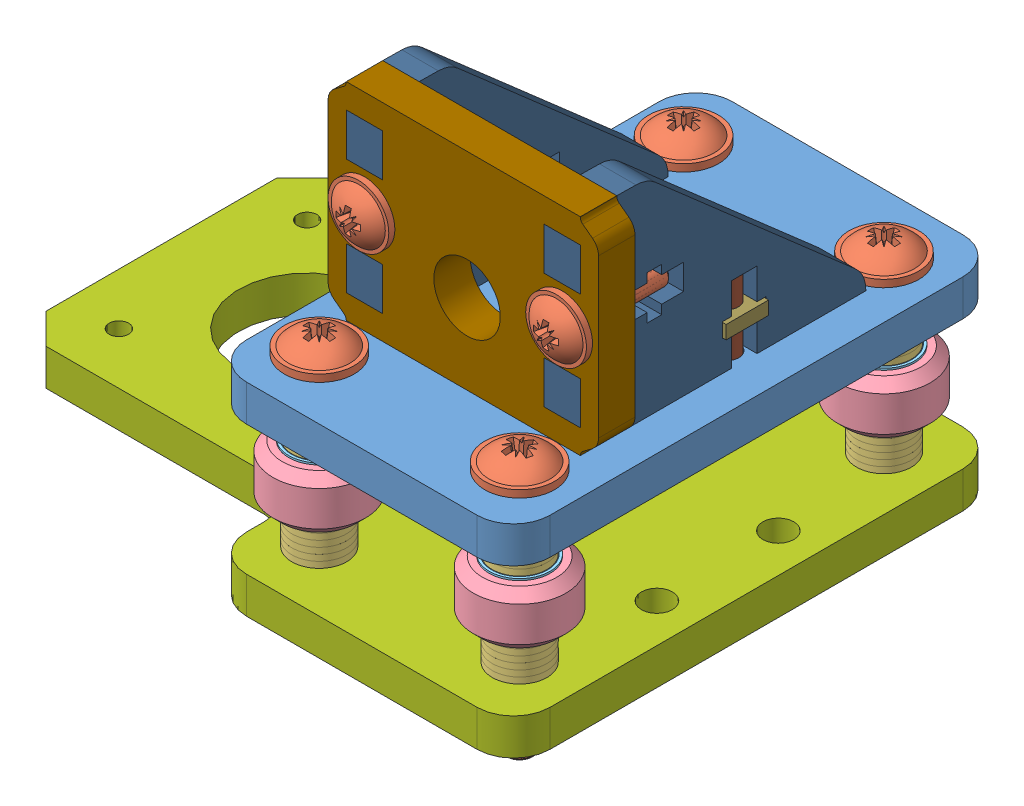
SolidWorks assembly carriage_y_l, configuration По умолчанию. Lengths in mm.
Overall size (131.86 74.07 98.19).
87 component instances, 12 part files, 142 mates.
Components (placement in the parent):
- top_y_l-4: top_y_l [По умолчанию] at origin size (50 6 80)
- DIN967-1: DIN967 [М5х40] at (-17 9.55 -30) x (0 -1 0) z (0 0 1) size (43.47 34 34.42)
- DIN967-2: DIN967 [М5х40] at (-17 9.55 30) x (0 -1 0) z (0 0 1) size (43.47 34 34.42)
- DIN967-3: DIN967 [М5х40] at (16 9.55 -30) x (0 -1 0) z (0 0 1) size (43.47 34 34.42)
- DIN967-4: DIN967 [М5х40] at (16 9.55 30) x (0 -1 0) z (0.973575 0 0.228367) size (43.47 34 34.42)
- din433_m5-1: din433_m5 [По умолчанию] at (16 0 30) x (1 0 0) z (0 -1 0) size (9 9 1)
- din433_m5-2: din433_m5 [По умолчанию] at (16 -2 30) x (-0.882011 0 -0.471229) z (0 1 0) size (9 9 1)
- din433_m5-3: din433_m5 [По умолчанию] at (16 -3 30) x (-0.882011 0 -0.471229) z (0 1 0) size (9 9 1)
- din433_m5-4: din433_m5 [По умолчанию] at (16 -4 30) x (-0.882011 0 -0.471229) z (0 1 0) size (9 9 1)
- din433_m5-5: din433_m5 [По умолчанию] at (16 -5 30) x (-0.986157 0 -0.165812) z (0 1 0) size (9 9 1)
- din433_m5-6: din433_m5 [По умолчанию] at (16 -3 -30) x (-0.882011 0 -0.471229) z (0 1 0) size (9 9 1)
- din433_m5-7: din433_m5 [По умолчанию] at (16 -2 -30) x (-0.882011 0 -0.471229) z (0 1 0) size (9 9 1)
- din433_m5-8: din433_m5 [По умолчанию] at (16 -1 -30) x (-0.706556 0 -0.707657) z (0 1 0) size (9 9 1)
- din433_m5-9: din433_m5 [По умолчанию] at (16 -4 -30) x (-0.882011 0 -0.471229) z (0 1 0) size (9 9 1)
- din433_m5-10: din433_m5 [По умолчанию] at (16 -5 -30) x (0.996128 0 0.087912) z (0 -1 0) size (9 9 1)
- din433_m5-11: din433_m5 [По умолчанию] at (16 -5 -30) x (-0.882011 0 -0.471229) z (0 1 0) size (9 9 1)
- din433_m5-12: din433_m5 [По умолчанию] at (-17 -3 30) x (-0.955012 0 -0.296566) z (0 1 0) size (9 9 1)
- din433_m5-13: din433_m5 [По умолчанию] at (-17 -4 30) x (-0.955012 0 -0.296566) z (0 1 0) size (9 9 1)
- din433_m5-14: din433_m5 [По умолчанию] at (-17 -5 30) x (-0.827257 0 -0.561823) z (0 1 0) size (9 9 1)
- din433_m5-15: din433_m5 [По умолчанию] at (-17 -2 30) x (-0.955012 0 -0.296566) z (0 1 0) size (9 9 1)
- din433_m5-16: din433_m5 [По умолчанию] at (-17 0 30) x (0.982082 0 -0.188455) z (0 -1 0) size (9 9 1)
- din433_m5-17: din433_m5 [По умолчанию] at (-17 -2 -30) x (-0.996489 0 -0.083718) z (0 1 0) size (9 9 1)
- din433_m5-18: din433_m5 [По умолчанию] at (-17 -3 -30) x (-0.996489 0 -0.083718) z (0 1 0) size (9 9 1)
- din433_m5-19: din433_m5 [По умолчанию] at (-17 -4 -30) x (-0.928921 0 -0.370279) z (0 1 0) size (9 9 1)
- din433_m5-20: din433_m5 [По умолчанию] at (-17 -1 -30) x (-0.996489 0 -0.083718) z (0 1 0) size (9 9 1)
- din433_m5-28: din433_m5 [По умолчанию] at (-17 -5 -30) x (0.980186 0 0.198081) z (0 -1 0) size (9 9 1)
- din433_m5-29: din433_m5 [По умолчанию] at (-17 -4 -30) x (0.980186 0 0.198081) z (0 -1 0) size (9 9 1)
- din433_m5-27: din433_m5 [По умолчанию] at (16 -5 30) x (0.91627 0 0.40056) z (0 -1 0) size (9 9 1)
- din433_m5-21: din433_m5 [По умолчанию] at (-17 -6 30) x (-0.552382 0 -0.833591) z (0 1 0) size (9 9 1)
- Delrin Mini V Wheel Kit-1: Delrin Mini V Wheel Kit [По умолчанию] at (-17 -10.7 30) x (0 1 0) z (0 0 1) size (9.4 15.23 15.23)
  - Delrin Mini V Wheel-1: Delrin Mini V Wheel [Default] at origin size (8.8 15.23 15.23)
  - Mini Ball Bearing 105zz 5x10x4-1: Mini Ball Bearing 105zz 5x10x4 [Default] at (2.6 0 0) size (4.2 10 10)
  - Mini Ball Bearing 105zz 5x10x4-2: Mini Ball Bearing 105zz 5x10x4 [Default] at (-2.6 0 0) size (4.2 10 10)
  - Mini V Wheel Precision Shim-2: Mini V Wheel Precision Shim [По умолчанию] at (-0.5 0 0) size (1 8 8)
- din433_m5-30: din433_m5 [По умолчанию] at (-17 -19.4 30) x (0.999952 0 0.009811) z (0 -1 0) size (9 9 1)
- din433_m5-31: din433_m5 [По умолчанию] at (-17 -20.4 30) x (0.999952 0 0.009811) z (0 -1 0) size (9 9 1)
- din433_m5-32: din433_m5 [По умолчанию] at (-17 -16.4 30) x (-0.994411 0 0.105575) z (0 1 0) size (9 9 1)
- din433_m5-33: din433_m5 [По умолчанию] at (-17 -19.4 30) x (-0.982057 0 -0.188585) z (0 1 0) size (9 9 1)
- din433_m5-34: din433_m5 [По умолчанию] at (-17 -18.4 30) x (-0.994411 0 0.105575) z (0 1 0) size (9 9 1)
- din433_m5-35: din433_m5 [По умолчанию] at (-17 -17.4 30) x (-0.994411 0 0.105575) z (0 1 0) size (9 9 1)
- Delrin Mini V Wheel Kit-2: Delrin Mini V Wheel Kit [По умолчанию] at (-17 -10.7 -30) x (0 -1 0) z (0.990454 0 -0.137844) size (9.4 15.23 15.23)
  - Delrin Mini V Wheel-1: Delrin Mini V Wheel [Default] at origin size (8.8 15.23 15.23)
  - Mini Ball Bearing 105zz 5x10x4-1: Mini Ball Bearing 105zz 5x10x4 [Default] at (2.6 0 0) size (4.2 10 10)
  - Mini Ball Bearing 105zz 5x10x4-2: Mini Ball Bearing 105zz 5x10x4 [Default] at (-2.6 0 0) size (4.2 10 10)
  - Mini V Wheel Precision Shim-2: Mini V Wheel Precision Shim [По умолчанию] at (-0.5 0 0) size (1 8 8)
- din433_m5-42: din433_m5 [По умолчанию] at (-17 -20.4 -30) x (0.983884 0 -0.17881) z (0 -1 0) size (9 9 1)
- din433_m5-43: din433_m5 [По умолчанию] at (-17 -16.4 -30) x (-0.956697 0 0.291085) z (0 1 0) size (9 9 1)
- din433_m5-44: din433_m5 [По умолчанию] at (-17 -19.4 -30) x (-1 0 -0.000132) z (0 1 0) size (9 9 1)
- din433_m5-45: din433_m5 [По умолчанию] at (-17 -18.4 -30) x (-0.956697 0 0.291085) z (0 1 0) size (9 9 1)
- din433_m5-46: din433_m5 [По умолчанию] at (-17 -17.4 -30) x (-0.956697 0 0.291085) z (0 1 0) size (9 9 1)
- din433_m5-47: din433_m5 [По умолчанию] at (-17 -19.4 -30) x (0.983884 0 -0.17881) z (0 -1 0) size (9 9 1)
- Delrin Mini V Wheel Kit-3: Delrin Mini V Wheel Kit [По умолчанию] at (16 -10.7 -30) x (0 1 0) z (0 0 1) size (9.4 15.23 15.23)
  - Delrin Mini V Wheel-1: Delrin Mini V Wheel [Default] at origin size (8.8 15.23 15.23)
  - Mini Ball Bearing 105zz 5x10x4-1: Mini Ball Bearing 105zz 5x10x4 [Default] at (2.6 0 0) size (4.2 10 10)
  - Mini Ball Bearing 105zz 5x10x4-2: Mini Ball Bearing 105zz 5x10x4 [Default] at (-2.6 0 0) size (4.2 10 10)
  - Mini V Wheel Precision Shim-2: Mini V Wheel Precision Shim [По умолчанию] at (-0.5 0 0) size (1 8 8)
- Delrin Mini V Wheel Kit-4: Delrin Mini V Wheel Kit [По умолчанию] at (16 -10.7 30) x (0 -1 0) z (-0.546944 0 0.837169) size (9.4 15.23 15.23)
  - Delrin Mini V Wheel-1: Delrin Mini V Wheel [Default] at origin size (8.8 15.23 15.23)
  - Mini Ball Bearing 105zz 5x10x4-1: Mini Ball Bearing 105zz 5x10x4 [Default] at (2.6 0 0) size (4.2 10 10)
  - Mini Ball Bearing 105zz 5x10x4-2: Mini Ball Bearing 105zz 5x10x4 [Default] at (-2.6 0 0) size (4.2 10 10)
  - Mini V Wheel Precision Shim-2: Mini V Wheel Precision Shim [По умолчанию] at (-0.5 0 0) size (1 8 8)
- din433_m5-54: din433_m5 [По умолчанию] at (16 -16.4 30) x (-0.124351 0 0.992238) z (0 1 0) size (9 9 1)
- din433_m5-55: din433_m5 [По умолчанию] at (16 -19.4 30) x (-0.982107 0 0.188325) z (0 1 0) size (9 9 1)
- din433_m5-56: din433_m5 [По умолчанию] at (16 -18.4 30) x (-0.884699 0 0.466164) z (0 1 0) size (9 9 1)
- din433_m5-57: din433_m5 [По умолчанию] at (16 -17.4 30) x (-0.884699 0 0.466164) z (0 1 0) size (9 9 1)
- din433_m5-58: din433_m5 [По умолчанию] at (16 -19.4 30) x (0.932557 0 -0.361024) z (0 -1 0) size (9 9 1)
- din433_m5-59: din433_m5 [По умолчанию] at (16 -20.4 30) x (0.932557 0 -0.361024) z (0 -1 0) size (9 9 1)
- din433_m5-132: din433_m5 [По умолчанию] at (16 -18.4 -30) x (-0.884699 0 0.466164) z (0 1 0) size (9 9 1)
- din433_m5-133: din433_m5 [По умолчанию] at (16 -20.4 -30) x (0.932557 0 -0.361024) z (0 -1 0) size (9 9 1)
- din433_m5-134: din433_m5 [По умолчанию] at (16 -19.4 -30) x (0.932557 0 -0.361024) z (0 -1 0) size (9 9 1)
- din433_m5-135: din433_m5 [По умолчанию] at (16 -17.4 -30) x (-0.884699 0 0.466164) z (0 1 0) size (9 9 1)
- din433_m5-136: din433_m5 [По умолчанию] at (16 -19.4 -30) x (-0.982107 0 0.188325) z (0 1 0) size (9 9 1)
- din433_m5-137: din433_m5 [По умолчанию] at (16 -16.4 -30) x (0.998156 0 0.060708) z (0 1 0) size (9 9 1)
- bottom_y_l-2: bottom_y_l [По умолчанию] at (0 -27.4 0) size (131.86 6 80)
- DIN 985-1: DIN 985 [Verzle DIN 985 - M5] at (-17 -27.4 -30) x (0 1 0) z (1 0 0) size (5 9.24 8)
- DIN 985-2: DIN 985 [Verzle DIN 985 - M5] at (-17 -27.4 30) x (0 1 0) z (1 0 0) size (5 9.24 8)
- DIN 985-3: DIN 985 [Verzle DIN 985 - M5] at (16 -27.4 -30) x (0 1 0) z (1 0 0) size (5 9.24 8)
- DIN 985-4: DIN 985 [Verzle DIN 985 - M5] at (16 -27.4 30) x (0 1 0) z (1 0 0) size (5 9.24 8)
- carriage_y_console-1: carriage_y_console [По умолчанию] at (3.7454 -0.1715 23) x (-1 0 0) z (0 0 -1) size (44.55 34.07 6)
- carriage_y_console_rectangel-1: carriage_y_console_rectangel [По умолчанию] at (19 -0.0784 23) x (0 0 -1) z (1 0 0) size (47 40.07 6)
- carriage_y_console_rectangel-2: carriage_y_console_rectangel [По умолчанию] at (-13.55 -0.0784 23) x (0 0 -1) z (1 0 0) size (47 40.07 6)
- DIN 7991-1: DIN 7991 [ISO 7991 M04 x  16] at (-16.55 0 -4) x (0 1 0) z (-1 0 0) size (18.3 40 22.08)
- din 562 m4din-1: din 562 m4din [По умолчанию] at (-16.55 11 -4) x (0 0 -1) z (0 1 0) size (7 7 2.2)
- DIN 7991-2: DIN 7991 [ISO 7991 M04 x  16] at (16 0 -4) x (0 1 0) z (1 0 0) size (18.3 40 22.08)
- din 562 m4din-2: din 562 m4din [По умолчанию] at (16 11 -4) x (0 0 1) z (0 1 0) size (7 7 2.2)
- DIN967-5: DIN967 [M4х16] at (-16.55 23 26.05) x (0 0 -1) z (1 0 0) size (18.96 34 34.42)
- DIN967-6: DIN967 [M4х16] at (16 23 26.05) x (0 0 -1) z (1 0 0) size (18.96 34 34.42)
Mates (geometry in assembly coordinates):
- Концентричный11: concentric anti-aligned: cylinder of top-4 through (-17 6 -30) axis (0 -1 0) radius 2.55; cylinder of DIN967-1 through (-17 15.9 -30) axis (0 1 0) radius 5.75
- Совпадение11: coincident anti-aligned: plane of top-4 through (19 6 -34) normal (0 1 0); plane of DIN967-1 through (-14.5 6 -30) normal (0 -1 0)
- Концентричный21: concentric anti-aligned: cylinder of top-4 through (-17 6 30) axis (0 -1 0) radius 2.55; cylinder of DIN967-2 through (-17 15.9 30) axis (0 1 0) radius 5.75
- Совпадение21: coincident anti-aligned: plane of top-4 through (19 6 -34) normal (0 1 0); plane of DIN967-2 through (-14.5 6 30) normal (0 -1 0)
- Концентричный31: concentric anti-aligned: cylinder of DIN967-3 through (16 15.9 -30) axis (0 1 0) radius 5.75; circle of carriage_axis_y_plywood_left-1
- Совпадение31: coincident anti-aligned: plane of top-4 through (19 6 -34) normal (0 1 0); plane of DIN967-3 through (18.5 6 -30) normal (0 -1 0)
- Совпадение41: coincident anti-aligned: plane of top-4 through (19 6 -34) normal (0 1 0); plane of DIN967-4 through (16.5709 6 27.5661) normal (0 -1 0)
- Концентричный5: concentric anti-aligned: cylinder of top-4 through (16 6 30) axis (0 -1 0) radius 2.55; cylinder of DIN967-4 through (16 15.9 30) axis (0 1 0) radius 2.5
- Совпадение5: coincident anti-aligned: plane of top-4 through (19 0 -34) normal (0 -1 0); plane of din433_m5-1 through (16 0 30) normal (0 1 0)
- Концентричный6: concentric anti-aligned: cylinder of DIN967-4 through (16 15.9 30) axis (0 1 0) radius 2.5; circle of din433_m5-1
- Концентричный7: concentric aligned: cylinder of DIN967-4 through (16 15.9 30) axis (0 1 0) radius 2.5; circle of din433_m5-2
- Совпадение7: coincident anti-aligned: plane of din433_m5-1 through (16 -1 30) normal (0 -1 0); plane of din433_m5-2 through (16 -1 30) normal (0 1 0)
- Совпадение10: coincident anti-aligned: plane of din433_m5-3 through (16 -3 30) normal (0 -1 0); plane of din433_m5-4 through (16 -3 30) normal (0 1 0)
- Совпадение11: coincident aligned: circle of din433_m5-3; circle of din433_m5-4
- Совпадение12: coincident anti-aligned: plane of din433_m5-4 through (16 -4 30) normal (0 -1 0); plane of din433_m5-5 through (16 -4 30) normal (0 1 0)
- Совпадение13: coincident aligned: circle of din433_m5-4; circle of din433_m5-5
- Совпадение14: coincident anti-aligned: plane of din433_m5-2 through (16 -2 30) normal (0 -1 0); plane of din433_m5-3 through (16 -2 30) normal (0 1 0)
- Совпадение15: coincident aligned: circle of din433_m5-2; circle of din433_m5-3
- Совпадение16: coincident anti-aligned: plane of top-4 through (19 0 -34) normal (0 -1 0); plane of din433_m5-8 through (16 0 -30) normal (0 1 0)
- Концентричный8: concentric aligned: cylinder of DIN967-3 through (16 15.9 -30) axis (0 1 0) radius 2.5; circle of din433_m5-8
- Совпадение17: coincident anti-aligned: plane of din433_m5-7 through (16 -1 -30) normal (0 1 0); plane of din433_m5-8 through (16 -1 -30) normal (0 -1 0)
- Совпадение18: coincident aligned: circle of din433_m5-7; circle of din433_m5-8
- Совпадение19: coincident anti-aligned: plane of din433_m5-6 through (16 -2 -30) normal (0 1 0); plane of din433_m5-7 through (16 -2 -30) normal (0 -1 0)
- Концентричный9: concentric aligned: cylinder of DIN967-3 through (16 15.9 -30) axis (0 1 0) radius 2.5; circle of din433_m5-6
- Совпадение20: coincident anti-aligned: plane of din433_m5-6 through (16 -3 -30) normal (0 -1 0); plane of din433_m5-9 through (16 -3 -30) normal (0 1 0)
- Концентричный10: concentric aligned: cylinder of DIN967-3 through (16 15.9 -30) axis (0 1 0) radius 2.5; circle of din433_m5-9
- Совпадение22: coincident anti-aligned: plane of din433_m5-9 through (16 -4 -30) normal (0 -1 0); plane of din433_m5-11 through (16 -4 -30) normal (0 1 0)
- Концентричный11: concentric aligned: cylinder of DIN967-3 through (16 15.9 -30) axis (0 1 0) radius 2.5; circle of din433_m5-11
- Совпадение23: coincident anti-aligned: plane of din433_m5-10 through (16 -5 -30) normal (0 1 0); plane of din433_m5-11 through (16 -5 -30) normal (0 -1 0)
- Концентричный13: concentric anti-aligned: cylinder of DIN967-3 through (16 15.9 -30) axis (0 1 0) radius 2.5; circle of din433_m5-10
- Совпадение24: coincident anti-aligned: plane of din433_m5-15 through (-17 -1 30) normal (0 1 0); plane of din433_m5-16 through (-17 -1 30) normal (0 -1 0)
- Совпадение25: coincident anti-aligned: plane of din433_m5-12 through (-17 -3 30) normal (0 -1 0); plane of din433_m5-13 through (-17 -3 30) normal (0 1 0)
- Совпадение26: coincident aligned: circle of din433_m5-12; circle of din433_m5-13
- Совпадение27: coincident anti-aligned: plane of din433_m5-13 through (-17 -4 30) normal (0 -1 0); plane of din433_m5-14 through (-17 -4 30) normal (0 1 0)
- Совпадение28: coincident aligned: circle of din433_m5-13; circle of din433_m5-14
- Совпадение29: coincident anti-aligned: plane of din433_m5-12 through (-17 -2 30) normal (0 1 0); plane of din433_m5-15 through (-17 -2 30) normal (0 -1 0)
- Совпадение30: coincident aligned: circle of din433_m5-12; circle of din433_m5-15
- Совпадение33: coincident anti-aligned: plane of din433_m5-17 through (-17 -2 -30) normal (0 -1 0); plane of din433_m5-18 through (-17 -2 -30) normal (0 1 0)
- Совпадение34: coincident aligned: circle of din433_m5-17; circle of din433_m5-18
- Совпадение35: coincident anti-aligned: plane of din433_m5-18 through (-17 -3 -30) normal (0 -1 0); plane of din433_m5-19 through (-17 -3 -30) normal (0 1 0)
- Совпадение36: coincident aligned: circle of din433_m5-18; circle of din433_m5-19
- Совпадение37: coincident anti-aligned: plane of din433_m5-17 through (-17 -1 -30) normal (0 1 0); plane of din433_m5-20 through (-17 -1 -30) normal (0 -1 0)
- Совпадение38: coincident aligned: circle of din433_m5-17; circle of din433_m5-20
- Концентричный15: concentric aligned: cylinder of DIN967-2 through (-17 15.9 30) axis (0 1 0) radius 2.5; circle of din433_m5-14
- Концентричный16: concentric anti-aligned: cylinder of DIN967-2 through (-17 15.9 30) axis (0 1 0) radius 2.5; circle of din433_m5-16
- Совпадение54: coincident anti-aligned: plane of din433_m5-14 through (-17 -5 30) normal (0 -1 0); plane of din433_m5-21 through (-17 -5 30) normal (0 1 0)
- Концентричный17: concentric aligned: cylinder of DIN967-2 through (-17 15.9 30) axis (0 1 0) radius 2.5; circle of din433_m5-21
- Совпадение55: coincident anti-aligned: plane of din433_m5-5 through (16 -5 30) normal (0 -1 0); plane of din433_m5-27 through (16 -5 30) normal (0 1 0)
- Концентричный18: concentric anti-aligned: cylinder of DIN967-4 through (16 15.9 30) axis (0 1 0) radius 2.5; circle of din433_m5-27
- Концентричный19: concentric aligned: cylinder of DIN967-1 through (-17 15.9 -30) axis (0 1 0) radius 2.5; circle of din433_m5-20
- Совпадение56: coincident anti-aligned: plane of din433_m5-19 through (-17 -4 -30) normal (0 -1 0); plane of din433_m5-29 through (-17 -4 -30) normal (0 1 0)
- Концентричный20: concentric anti-aligned: cylinder of DIN967-1 through (-17 15.9 -30) axis (0 1 0) radius 2.5; circle of din433_m5-29
- Совпадение57: coincident anti-aligned: plane of din433_m5-28 through (-17 -5 -30) normal (0 1 0); plane of din433_m5-29 through (-17 -5 -30) normal (0 -1 0)
- Концентричный21: concentric anti-aligned: cylinder of DIN967-1 through (-17 15.9 -30) axis (0 1 0) radius 2.5; circle of din433_m5-28
- Совпадение58: coincident anti-aligned: plane of top-4 through (19 0 -34) normal (0 -1 0); plane of din433_m5-20 through (-17 0 -30) normal (0 1 0)
- Совпадение59: coincident anti-aligned: plane of din433_m5-21 through (-17 -6 30) normal (0 -1 0); plane of Delrin Mini V Wheel Kit-1/Mini Ball Bearing 105zz 5x10x4-1 through (-19.5 -6 30) normal (0 1 0)
- Совпадение60: coincident aligned: cylinder of DIN967-2 through (-17 15.9 30) axis (0 1 0) radius 2.5; circle of Delrin Mini V Wheel Kit-1/Mini Ball Bearing 105zz 5x10x4-2
- Совпадение61: coincident anti-aligned: plane of din433_m5-34 through (-17 -17.4 30) normal (0 1 0); plane of din433_m5-35 through (-17 -17.4 30) normal (0 -1 0)
- Совпадение62: coincident aligned: circle of din433_m5-34; circle of din433_m5-35
- Совпадение63: coincident anti-aligned: plane of din433_m5-33 through (-17 -18.4 30) normal (0 1 0); plane of din433_m5-34 through (-17 -18.4 30) normal (0 -1 0)
- Совпадение64: coincident aligned: circle of din433_m5-33; circle of din433_m5-34
- Совпадение65: coincident anti-aligned: plane of din433_m5-32 through (-17 -16.4 30) normal (0 -1 0); plane of din433_m5-35 through (-17 -16.4 30) normal (0 1 0)
- Совпадение67: coincident anti-aligned: plane of din433_m5-30 through (-17 -19.4 30) normal (0 1 0); plane of din433_m5-33 through (-17 -19.4 30) normal (0 -1 0)
- Совпадение68: coincident anti-aligned: plane of din433_m5-30 through (-17 -20.4 30) normal (0 -1 0); plane of din433_m5-31 through (-17 -20.4 30) normal (0 1 0)
- Совпадение80: coincident anti-aligned: plane of Delrin Mini V Wheel Kit-1/Mini Ball Bearing 105zz 5x10x4-2 through (-19.5 -15.4 30) normal (0 -1 0); plane of din433_m5-32 through (-17 -15.4 30) normal (0 1 0)
- Концентричный22: concentric aligned: cylinder of DIN967-2 through (-17 15.9 30) axis (0 1 0) radius 2.5; circle of din433_m5-32
- Концентричный23: concentric aligned: cylinder of DIN967-2 through (-17 15.9 30) axis (0 1 0) radius 2.5; circle of din433_m5-35
- Концентричный24: concentric anti-aligned: cylinder of DIN967-2 through (-17 15.9 30) axis (0 1 0) radius 2.5; circle of din433_m5-30
- Концентричный25: concentric aligned: cylinder of DIN967-2 through (-17 15.9 30) axis (0 1 0) radius 2.5; cylinder of din433_m5-31 through (-17 -21.4 30) axis (0 1 0) radius 4.5
- Совпадение81: coincident anti-aligned: plane of din433_m5-28 through (-17 -6 -30) normal (0 -1 0); plane of Delrin Mini V Wheel Kit-2/Mini Ball Bearing 105zz 5x10x4-2 through (-17.3446 -6 -32.4761) normal (0 1 0)
- Совпадение82: coincident anti-aligned: cylinder of DIN967-1 through (-17 15.9 -30) axis (0 1 0) radius 2.5; circle of Delrin Mini V Wheel Kit-2/Mini Ball Bearing 105zz 5x10x4-1
- Совпадение83: coincident anti-aligned: plane of din433_m5-45 through (-17 -17.4 -30) normal (0 1 0); plane of din433_m5-46 through (-17 -17.4 -30) normal (0 -1 0)
- Совпадение84: coincident aligned: circle of din433_m5-45; circle of din433_m5-46
- Совпадение85: coincident anti-aligned: plane of din433_m5-44 through (-17 -18.4 -30) normal (0 1 0); plane of din433_m5-45 through (-17 -18.4 -30) normal (0 -1 0)
- Совпадение86: coincident aligned: circle of din433_m5-44; circle of din433_m5-45
- Совпадение87: coincident anti-aligned: plane of din433_m5-43 through (-17 -16.4 -30) normal (0 -1 0); plane of din433_m5-46 through (-17 -16.4 -30) normal (0 1 0)
- Совпадение88: coincident anti-aligned: plane of din433_m5-44 through (-17 -19.4 -30) normal (0 -1 0); plane of din433_m5-47 through (-17 -19.4 -30) normal (0 1 0)
- Совпадение89: coincident anti-aligned: plane of din433_m5-42 through (-17 -20.4 -30) normal (0 1 0); plane of din433_m5-47 through (-17 -20.4 -30) normal (0 -1 0)
- Совпадение99: coincident anti-aligned: plane of top-4 through (19 0 -34) normal (0 -1 0); plane of din433_m5-16 through (-17 0 30) normal (0 1 0)
- Совпадение100: coincident anti-aligned: plane of Delrin Mini V Wheel Kit-2/Mini Ball Bearing 105zz 5x10x4-1 through (-17.3446 -15.4 -32.4761) normal (0 -1 0); plane of din433_m5-43 through (-17 -15.4 -30) normal (0 1 0)
- Концентричный26: concentric anti-aligned: circle of din433_m5-42; circle of din433_m5-43
- Концентричный27: concentric anti-aligned: circle of din433_m5-43; circle of din433_m5-47
- Концентричный28: concentric anti-aligned: circle of din433_m5-42; circle of din433_m5-44
- Концентричный29: concentric aligned: circle of Delrin Mini V Wheel Kit-2/Mini Ball Bearing 105zz 5x10x4-1; cylinder of din433_m5-43 through (-17 -15.4 -30) axis (0 -1 0) radius 4.5
- Совпадение104: coincident anti-aligned: plane of din433_m5-10 through (16 -6 -30) normal (0 -1 0); plane of Delrin Mini V Wheel Kit-3/Mini Ball Bearing 105zz 5x10x4-1 through (13.5 -6 -30) normal (0 1 0)
- Совпадение105: coincident aligned: cylinder of DIN967-3 through (16 15.9 -30) axis (0 1 0) radius 2.5; circle of Delrin Mini V Wheel Kit-3/Mini Ball Bearing 105zz 5x10x4-2
- Совпадение106: coincident anti-aligned: plane of din433_m5-27 through (16 -6 30) normal (0 -1 0); plane of Delrin Mini V Wheel Kit-4/Mini Ball Bearing 105zz 5x10x4-2 through (18.0929 -6 31.3674) normal (0 1 0)
- Концентричный30: concentric anti-aligned: cylinder of DIN967-4 through (16 15.9 30) axis (0 1 0) radius 2.5; cylinder of Delrin Mini V Wheel Kit-4/Mini Ball Bearing 105zz 5x10x4-1 through (16 -13.3 30) axis (0 -1 0) radius 2.5
- Совпадение107: coincident anti-aligned: plane of din433_m5-56 through (16 -17.4 30) normal (0 1 0); plane of din433_m5-57 through (16 -17.4 30) normal (0 -1 0)
- Совпадение108: coincident aligned: circle of din433_m5-56; circle of din433_m5-57
- Совпадение109: coincident anti-aligned: plane of din433_m5-55 through (16 -18.4 30) normal (0 1 0); plane of din433_m5-56 through (16 -18.4 30) normal (0 -1 0)
- Совпадение110: coincident aligned: circle of din433_m5-55; circle of din433_m5-56
- Совпадение111: coincident anti-aligned: plane of din433_m5-54 through (16 -16.4 30) normal (0 -1 0); plane of din433_m5-57 through (16 -16.4 30) normal (0 1 0)
- Совпадение112: coincident anti-aligned: plane of din433_m5-55 through (16 -19.4 30) normal (0 -1 0); plane of din433_m5-58 through (16 -19.4 30) normal (0 1 0)
- Совпадение113: coincident anti-aligned: plane of din433_m5-58 through (16 -20.4 30) normal (0 -1 0); plane of din433_m5-59 through (16 -20.4 30) normal (0 1 0)
- Концентричный31: concentric anti-aligned: circle of din433_m5-54; circle of din433_m5-59
- Концентричный32: concentric anti-aligned: circle of din433_m5-54; circle of din433_m5-58
- Концентричный33: concentric anti-aligned: circle of din433_m5-55; circle of din433_m5-59
- Концентричный83: concentric anti-aligned: circle of din433_m5-133; circle of din433_m5-136
- Совпадение200: coincident anti-aligned: plane of din433_m5-132 through (16 -18.4 -30) normal (0 -1 0); plane of din433_m5-136 through (16 -18.4 -30) normal (0 1 0)
- Совпадение201: coincident aligned: circle of din433_m5-132; circle of din433_m5-135
- Совпадение202: coincident anti-aligned: plane of din433_m5-132 through (16 -17.4 -30) normal (0 1 0); plane of din433_m5-135 through (16 -17.4 -30) normal (0 -1 0)
- Концентричный84: concentric anti-aligned: circle of din433_m5-134; circle of din433_m5-137
- Совпадение203: coincident anti-aligned: plane of din433_m5-135 through (16 -16.4 -30) normal (0 1 0); plane of din433_m5-137 through (16 -16.4 -30) normal (0 -1 0)
- Концентричный85: concentric anti-aligned: circle of din433_m5-133; circle of din433_m5-137
- Совпадение204: coincident anti-aligned: plane of din433_m5-134 through (16 -19.4 -30) normal (0 1 0); plane of din433_m5-136 through (16 -19.4 -30) normal (0 -1 0)
- Совпадение205: coincident aligned: circle of din433_m5-132; circle of din433_m5-136
- Совпадение206: coincident anti-aligned: plane of din433_m5-133 through (16 -20.4 -30) normal (0 1 0); plane of din433_m5-134 through (16 -20.4 -30) normal (0 -1 0)
- Совпадение207: coincident anti-aligned: plane of Delrin Mini V Wheel Kit-3/Mini Ball Bearing 105zz 5x10x4-2 through (13.5 -15.4 -30) normal (0 -1 0); plane of din433_m5-137 through (16 -15.4 -30) normal (0 1 0)
- Концентричный86: concentric aligned: cylinder of DIN967-3 through (16 15.9 -30) axis (0 1 0) radius 2.5; circle of din433_m5-137
- Совпадение208: coincident anti-aligned: plane of Delrin Mini V Wheel Kit-4/Mini Ball Bearing 105zz 5x10x4-1 through (18.0929 -15.4 31.3674) normal (0 -1 0); plane of din433_m5-54 through (16 -15.4 30) normal (0 1 0)
- Концентричный87: concentric aligned: cylinder of DIN967-4 through (16 15.9 30) axis (0 1 0) radius 2.5; circle of din433_m5-54
- Концентричный88: concentric anti-aligned: cylinder of DIN967-1 through (-17 15.9 -30) axis (0 1 0) radius 2.5; circle of carriage_axis_y_plywood_left-2
- Концентричный89: concentric anti-aligned: cylinder of DIN967-2 through (-17 15.9 30) axis (0 1 0) radius 2.5; circle of carriage_axis_y_plywood_left-2
- Совпадение210: coincident anti-aligned: plane of din433_m5-42 through (-17 -21.4 -30) normal (0 -1 0); plane of bottom_y_l-2 through (19 -21.4 -34) normal (0 1 0)
- Совпадение211: coincident anti-aligned: plane of bottom_y_l-2 through (19 -27.4 -34) normal (0 -1 0); plane of DIN 985-1 through (-17 -27.4 -30) normal (0 1 0)
- Концентричный90: concentric anti-aligned: cylinder of DIN967-1 through (-17 15.9 -30) axis (0 1 0) radius 2.5; cylinder of DIN 985-1 through (-17 -35.522 -30) axis (0 -1 0) radius 2.5
- Совпадение212: coincident anti-aligned: plane of bottom_y_l-2 through (19 -27.4 -34) normal (0 -1 0); plane of DIN 985-2 through (-17 -27.4 30) normal (0 1 0)
- Совпадение213: coincident anti-aligned: plane of bottom_y_l-2 through (19 -27.4 -34) normal (0 -1 0); plane of DIN 985-4 through (16 -27.4 30) normal (0 1 0)
- Совпадение214: coincident anti-aligned: plane of bottom_y_l-2 through (19 -27.4 -34) normal (0 -1 0); plane of DIN 985-3 through (16 -27.4 -30) normal (0 1 0)
- Концентричный91: concentric anti-aligned: cylinder of DIN967-2 through (-17 15.9 30) axis (0 1 0) radius 2.5; cylinder of DIN 985-2 through (-17 -35.522 30) axis (0 -1 0) radius 2.5
- Концентричный92: concentric anti-aligned: cylinder of DIN967-3 through (16 15.9 -30) axis (0 1 0) radius 2.5; cylinder of DIN 985-3 through (16 -35.522 -30) axis (0 -1 0) radius 2.5
- Концентричный93: concentric anti-aligned: cylinder of DIN967-4 through (16 15.9 30) axis (0 1 0) radius 2.5; cylinder of DIN 985-4 through (16 -35.522 30) axis (0 -1 0) radius 2.5
- Расстояние1: distance = 17 mm aligned: plane of carriage_y_console-1 through (3.7454 -0.1715 23) normal (0 0 1); plane of top_y_l-4 through (-19 6 40) normal (0 0 1)
- Совпадение224: coincident anti-aligned: plane of carriage_y_console-1 through (3.7454 -0.1715 17) normal (0 0 -1); plane of carriage_y_console_rectangel-2 through (-19.55 40.0693 17) normal (0 0 1)
- Совпадение225: coincident anti-aligned: plane of top_y_l-4 through (19 6 -34) normal (0 1 0); plane of carriage_y_console_rectangel-2 through (-19.55 6 -24) normal (0 -1 0)
- Совпадение226: coincident aligned: plane of carriage_y_console-1 through (-19.55 6 17) normal (-1 0 0); plane of carriage_y_console_rectangel-2 through (-19.55 6.2312 -19) normal (-1 0 0)
- Совпадение227: coincident anti-aligned: plane of top_y_l-4 through (19 6 -34) normal (0 1 0); plane of carriage_y_console-1 through (19 6 17) normal (0 -1 0)
- Расстояние3: distance = 5.45 mm aligned: plane of top_y_l-4 through (-25 6 34) normal (-1 0 0); plane of carriage_y_console-1 through (-19.55 6 17) normal (-1 0 0)
- Совпадение228: coincident aligned: plane of carriage_y_console-1 through (3.7454 -0.1715 23) normal (0 0 1); plane of carriage_y_console_rectangel-1 through (19 9.9682 23) normal (0 0 1)
- Совпадение233: coincident anti-aligned: plane of carriage_y_console_rectangel-2 through (-19.55 6.2312 -19) normal (-1 0 0); plane of DIN 7991-1 through (-19.55 0 -4) normal (1 0 0)
- Совпадение234: coincident aligned: plane of top_y_l-4 through (19 0 -34) normal (0 -1 0); plane of DIN 7991-1 through (-16.55 0 -4) normal (0 -1 0)
- Совпадение235: coincident aligned: plane of carriage_y_console_rectangel-2 through (-19.55 6 -24) normal (0 0 -1); plane of DIN 7991-1 through (-16.55 0 -24) normal (0 0 -1)
- Совпадение239: coincident: point of din 562 m4din-1; line of DIN 7991-1 through (-16.55 18.3 -4) axis (0 -1 0)
- Совпадение241: coincident anti-aligned: plane of carriage_y_console_rectangel-1 through (19 6.2312 -19) normal (1 0 0); plane of DIN 7991-2 through (19 0 -4) normal (-1 0 0)
- Совпадение242: coincident aligned: plane of top_y_l-4 through (19 0 -34) normal (0 -1 0); plane of DIN 7991-2 through (16 0 -4) normal (0 -1 0)
- Совпадение243: coincident anti-aligned: plane of carriage_y_console_rectangel-1 through (13 6 -24) normal (0 0 -1); plane of DIN 7991-2 through (16 0 -24) normal (0 0 1)
- Совпадение248: coincident: point of din 562 m4din-2; line of DIN 7991-2 through (16 18.3 -4) axis (0 -1 0)
- Концентричный991: concentric aligned: cylinder of carriage_y_console-1 through (-16.55 23 17) axis (0 0 1) radius 2.1; cylinder of DIN967-5 through (-16.55 23 32.4) axis (0 0 1) radius 5
- Совпадение2521: coincident anti-aligned: plane of carriage_y_console-1 through (3.7454 -0.1715 23) normal (0 0 1); plane of DIN967-5 through (-16.55 25 23) normal (0 0 -1)
- Концентричный1001: concentric aligned: cylinder of carriage_y_console-1 through (16 23 17) axis (0 0 1) radius 2.1; cylinder of DIN967-6 through (16 23 32.4) axis (0 0 1) radius 5
- Совпадение2531: coincident anti-aligned: plane of carriage_y_console-1 through (3.7454 -0.1715 23) normal (0 0 1); plane of DIN967-6 through (16 25 23) normal (0 0 -1)
